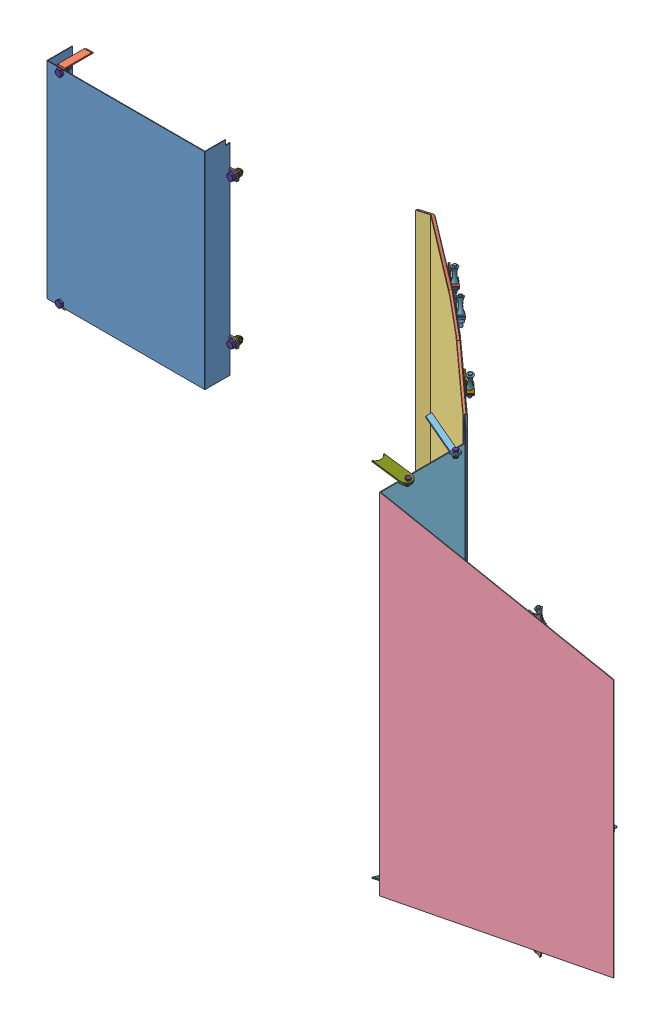
SolidWorks assembly PUTM-F-MS-SF-Firewall-Assembly, configuration Domyślna. Lengths in mm.
Overall size (1412.07 703.37 520.4).
48 component instances, 23 part files, 40 mates.
Components (placement in the parent):
- PUTM-F-MS-Firewall_Front_Aluminum_Skin-1: PUTM-F-MS-Firewall_Front_Aluminum_Skin [Domyślna] at origin size (454.25 703.37 375.65)
- PUTM-F-MS-Firewall_Front_Nomex_Core-1: PUTM-F-MS-Firewall_Front_Nomex_Core [Domyślna] at origin size (440.38 689.93 362.26)
- PUTM-F-MS-Firewall_Front_Kevlar_Skin-1: PUTM-F-MS-Firewall_Front_Kevlar_Skin [Domyślna] at origin size (443.17 703.37 363.44)
- PUTM-F-MS-SF-Firewall_Rear_Kevlar_Skin-1: PUTM-F-MS-SF-Firewall_Rear_Kevlar_Skin [Domyślna] at origin size (403.74 589.1 153.42)
- PUTM-F-MS-SF-Firewall_Rear_Aluminum_Skin-1: PUTM-F-MS-SF-Firewall_Rear_Aluminum_Skin [Domyślna] at origin size (403.45 588.99 153.27)
- PUTM-F-FR-MT-Firewall_Mountings_1-1: PUTM-F-FR-MT-Firewall_Mountings_1 [Domyślna] at origin size (23.76 25.91 22.22)
- PUTM-F-FR-MT-Firewall_Mounting_2-1: PUTM-F-FR-MT-Firewall_Mounting_2 [Domyślna] at origin size (28.34 29.8 21.98)
- PUTM-F-FR-MT-Firewall_Mountings_3-1: PUTM-F-FR-MT-Firewall_Mountings_3 [Domyślna] at origin size (22.95 27.42 25.34)
- LustroPUTM-F-FR-MT-Firewall_Mountings_3-2: LustroPUTM-F-FR-MT-Firewall_Mountings_3 [Domyślna] x (1 0 0) z (0 0 -1) size (22.95 27.42 25.34)
- LustroPUTM-F-FR-MT-Firewall_Mounting_2-2: LustroPUTM-F-FR-MT-Firewall_Mounting_2 [Domyślna] x (1 0 0) z (0 0 -1) size (28.34 29.8 21.98)
- LustroPUTM-F-FR-MT-Firewall_Mountings_1-2: LustroPUTM-F-FR-MT-Firewall_Mountings_1 [Domyślna] x (1 0 0) z (0 0 -1) size (23.76 25.91 22.22)
- PUTM-F-FR-MT-Firewall_Mountings_4-1: PUTM-F-FR-MT-Firewall_Mountings_4 [Domyślna] at origin size (26.62 34.9 12)
- LustroPUTM-F-FR-MT-Firewall_Mountings_4-2: LustroPUTM-F-FR-MT-Firewall_Mountings_4 [Domyślna] x (1 0 0) z (0 0 -1) size (26.62 34.9 12)
- PUTM-F-FR-MT-Firewall_Mounting_Cotter_Pin-1: PUTM-F-FR-MT-Firewall_Mounting_Cotter_Pin [Domyślna] at (801.96 -325.1095 318.2891) x (0.913742 -0.274504 0.299537) z (-0.223324 -0.955217 -0.194133) size (10 10 40.12)
- PUTM-F-FR-MT-Firewall_Mounting_Cotter_Pin-2: PUTM-F-FR-MT-Firewall_Mounting_Cotter_Pin [Domyślna] at (924.0825 -328.3705 419.9841) x (-0.719234 -0.211042 -0.66194) z (0.159337 -0.977459 0.138509) size (10 10 40.12)
- PUTM-F-FR-MT-Firewall_Mounting_Cotter_Pin-3: PUTM-F-FR-MT-Firewall_Mounting_Cotter_Pin [Domyślna] at (924.0825 328.3705 419.9841) x (0.719234 -0.211042 0.66194) z (0.159337 0.977459 0.138509) size (10 10 40.12)
- PUTM-F-FR-MT-Firewall_Mounting_Cotter_Pin-4: PUTM-F-FR-MT-Firewall_Mounting_Cotter_Pin [Domyślna] at (801.96 325.1095 318.2891) x (-0.913742 -0.274504 -0.299537) z (-0.223324 0.955217 -0.194133) size (10 10 40.12)
- PUTM-F-FR-MT-Firewall_Mounting_Cotter_Pin-5: PUTM-F-FR-MT-Firewall_Mounting_Cotter_Pin [Domyślna] at (726.1444 -299.3743 252.4949) x (0.879211 -0.045593 0.474246) z (-0.035265 -0.998908 -0.030655) size (10 10 40.12)
- PUTM-F-FR-MT-Firewall_Mounting_Cotter_Pin-6: PUTM-F-FR-MT-Firewall_Mounting_Cotter_Pin [Domyślna] at (726.1444 299.3743 252.4949) x (-0.879211 -0.045593 -0.474246) z (-0.035265 0.998908 -0.030655) size (10 10 40.12)
- PUTM-F-FR-MT-Firewall_Mounting_5-1: PUTM-F-FR-MT-Firewall_Mounting_5 [Domyślna] at origin size (54.5 12.56 22.24)
- LustroPUTM-F-FR-MT-Firewall_Mounting_5-2: LustroPUTM-F-FR-MT-Firewall_Mounting_5 [Domyślna] x (1 0 0) z (0 0 -1) size (54.5 12.56 22.24)
- PUTM-FT-FABORY_DIN933-1: PUTM-FT-FABORY_DIN933 [M4x10 [01210.040.010]] at (976.1401 295.562 577.4282) x (0.192233 0.981349 0) z (0 0 1) size (12.8 8.08 7)
- PUTM-FT-FABORY_DIN933-2: PUTM-FT-FABORY_DIN933 [M4x10 [01210.040.010]] at (976.1401 -295.562 577.4282) x (0.192233 -0.981349 0) z (0 0 1) size (12.8 8.08 7)
- PUTM-FT-FABORY_DIN985-1: PUTM-FT-FABORY_DIN985 [M4 [12348.040.001]] at (974.8329 288.8888 577.4282) x (0.943744 -0.184866 -0.274176) z (-0.192233 -0.981349 0) size (8.48 7.4 5.2)
- PUTM-FT-FABORY_DIN985-2: PUTM-FT-FABORY_DIN985 [M4 [12348.040.001]] at (974.8329 -288.8888 577.4282) x (0.899843 0.176267 -0.399013) z (-0.192233 0.981349 0) size (8.48 7.4 5.2)
- PUTM-F-MS-FW-LV_Firewall-1: PUTM-F-MS-FW-LV_Firewall [Domyślna] at origin size (277 344 42)
- PUTM-F-FR-MT-LV_Firewall_Mounting-2: PUTM-F-FR-MT-LV_Firewall_Mounting [Domyślna] at origin size (259.85 60.04 48.36)
- LustroPUTM-F-FR-MT-LV_Firewall_Mounting-3: LustroPUTM-F-FR-MT-LV_Firewall_Mounting [Domyślna] x (1 0 0) z (0 0 -1) size (259.85 60.04 48.36)
- PUTM-FT-FABORY_DIN933-3: PUTM-FT-FABORY_DIN933 [M6x16 [01210.060.016]] at (-28.852 -167.0403 157) x (0 0 1) z (0.417986 0.908453 0) size (20 11.55 10)
- PUTM-FT-FABORY_DIN933-5: PUTM-FT-FABORY_DIN933 [M6x16 [01210.060.016]] at (219 121 118.6) x (0 0 1) z (-0.91356 -0.406705 0) size (20 11.55 10)
- PUTM-FT-FABORY_DIN933-6: PUTM-FT-FABORY_DIN933 [M6x16 [01210.060.016]] at (-28.852 167.0403 157) x (0 0 1) z (-0.861615 -0.507562 0) size (20 11.55 10)
- PUTM-FT-FABORY_DIN933-10: PUTM-FT-FABORY_DIN933 [M6x16 [01210.060.016]] at (219 -121 118.6) x (0 0 1) z (-0.889465 -0.457003 0) size (20 11.55 10)
- PUTM-FT-FABORY_ISO7089-4: PUTM-FT-FABORY_ISO7089 [M6 [38093.060.001]] at (219 121 113) size (12 12 1.6)
- PUTM-FT-FABORY_ISO7089-5: PUTM-FT-FABORY_ISO7089 [M6 [38093.060.001]] at (219 -121 113) size (12 12 1.6)
- PUTM-FT-FABORY_ISO7089-15: PUTM-FT-FABORY_ISO7089 [M6 [38093.060.001]] at (219 121 107.4) size (12 12 1.6)
- PUTM-FT-FABORY_ISO7089-16: PUTM-FT-FABORY_ISO7089 [M6 [38093.060.001]] at (219 -121 107.4) size (12 12 1.6)
- PUTM-FT-FABORY_DIN985-5: PUTM-FT-FABORY_DIN985 [M6 [12348.060.001]] at (219 -121 107.4) x (-0.99791 -0.064621 0) z (0 0 -1) size (11.9 10.35 6.18)
- PUTM-FT-FABORY_DIN985-9: PUTM-FT-FABORY_DIN985 [M6 [12348.060.001]] at (219 121 107.4) x (-0.942958 0.332911 0) z (0 0 -1) size (11.9 10.35 6.18)
- PUTM-FT-FABORY_DIN985-10: PUTM-FT-FABORY_DIN985 [M6 [12348.060.001]] at (-28.852 167.0403 150) x (0.341689 -0.939813 0) z (0 0 -1) size (11.9 10.35 6.18)
- PUTM-FT-FABORY_DIN985-11: PUTM-FT-FABORY_DIN985 [M6 [12348.060.001]] at (-28.852 -167.0403 150) x (-0.356012 -0.934481 0) z (0 0 -1) size (11.9 10.35 6.18)
- PUTM-F-FR-MT-Firewall_Mounting_6-1: PUTM-F-FR-MT-Firewall_Mounting_6 [Domyślna] at origin size (50.77 32.6 10)
- PUTM-F-FR-MT-Firewall_Mounting_6-2: PUTM-F-FR-MT-Firewall_Mounting_6 [Domyślna] at (0 0 995.9987) x (1 0 0) z (0 0 -1) size (50.77 32.6 10)
- PUTM-FT-FABORY_DIN933-11: PUTM-FT-FABORY_DIN933 [M4x10 [01210.040.010]] at (975.5827 296.5593 497.9993) x (0 1 0) z (0 0 1) size (12.8 8.08 7)
- PUTM-FT-FABORY_DIN933-12: PUTM-FT-FABORY_DIN933 [M4x10 [01210.040.010]] at (975.5827 -296.5593 497.9993) x (0 -1 0) z (0 0 1) size (12.8 8.08 7)
- PUTM-FT-FABORY_DIN985-12: PUTM-FT-FABORY_DIN985 [M4 [12348.040.001]] at (975.5827 289.7593 497.9993) x (0.916837 0 0.399261) z (0 -1 0) size (8.48 7.4 5.2)
- PUTM-FT-FABORY_DIN985-13: PUTM-FT-FABORY_DIN985 [M4 [12348.040.001]] at (975.5827 -289.7593 497.9993) x (1 0 0) z (0 1 0) size (8.48 7.4 5.2)
- PUTM-F-FR-MT-Firewall_Mounting_Cotter_Pin-7: PUTM-F-FR-MT-Firewall_Mounting_Cotter_Pin [Domyślna] at (1230.8841 -235.5415 608.9586) x (-0.569792 0.172434 -0.803495) z (-0.289653 -0.957132 0) size (10 10 40.12)
- PUTM-F-FR-MT-Firewall_Mounting_Cotter_Pin-8: PUTM-F-FR-MT-Firewall_Mounting_Cotter_Pin [Domyślna] at (1230.8841 235.5415 608.9586) x (0.569792 0.172434 0.803495) z (-0.289653 0.957132 0) size (10 10 40.12)
Mates (geometry in assembly coordinates):
- Koncentryczne22: concentric anti-aligned: cylinder of LustroPUTM-F-FR-MT-Firewall_Mountings_3-2 through (919.9227 310.1146 418.6836) axis (0.159337 0.977459 0.138509) radius 2.5; cylinder of PUTM-F-FR-MT-Firewall_Mounting_Cotter_Pin-3 through (918.9666 304.2499 417.8525) axis (-0.159337 -0.977459 -0.138509) radius 2.5
- Wspólnie1: coincident anti-aligned: plane of LustroPUTM-F-FR-MT-Firewall_Mountings_3-2 through (932.1733 317.778 422.7079) normal (0.159337 0.977459 0.138509); plane of PUTM-F-FR-MT-Firewall_Mounting_Cotter_Pin-3 through (923.2066 319.8746 418.2271) normal (-0.159337 -0.977459 -0.138509)
- Koncentryczne23: concentric aligned: cylinder of PUTM-F-MS-Firewall_Front_Aluminum_Skin-1 through (804.0468 -318.5285 317.9542) axis (0.223324 0.955217 0.194133) radius 2.5; cylinder of PUTM-F-FR-MT-Firewall_Mounting_Cotter_Pin-1 through (808.0666 -301.3346 321.4486) axis (0.223324 0.955217 0.194133) radius 2.5
- Wspólnie2: coincident anti-aligned: plane of PUTM-F-FR-MT-Firewall_Mounting_2-1 through (814.9828 -319.5771 320.8357) normal (-0.223324 -0.955217 -0.194133); plane of PUTM-F-FR-MT-Firewall_Mounting_Cotter_Pin-1 through (803.6449 -316.8943 320.6778) normal (0.223324 0.955217 0.194133)
- Koncentryczne24: concentric anti-aligned: cylinder of PUTM-F-FR-MT-Firewall_Mountings_1-1 through (727.634 -280.6895 251.5296) axis (-0.035265 -0.998908 -0.030655) radius 2.5; cylinder of PUTM-F-FR-MT-Firewall_Mounting_Cotter_Pin-5 through (727.8456 -274.6961 251.7135) axis (0.035265 0.998908 0.030655) radius 2.5
- Wspólnie3: coincident anti-aligned: plane of PUTM-F-FR-MT-Firewall_Mountings_1-1 through (738.1005 -291.1458 254.0029) normal (-0.035265 -0.998908 -0.030655); plane of PUTM-F-FR-MT-Firewall_Mounting_Cotter_Pin-5 through (726.0935 -290.7042 253.4227) normal (0.035265 0.998908 0.030655)
- Koncentryczne27: concentric aligned: cylinder of PUTM-F-MS-FW-LV_Firewall-1 through (219 121 113) axis (0 0 -1) radius 3; cylinder of PUTM-FT-FABORY_DIN933-5 through (219 121 98.6) axis (0 0 -1) radius 3
- Koncentryczne32: concentric aligned: cylinder of PUTM-F-MS-FW-LV_Firewall-1 through (219 -121 113) axis (0 0 -1) radius 3; cylinder of PUTM-FT-FABORY_DIN933-10 through (219 -121 98.6) axis (0 0 -1) radius 3
- Koncentryczne38: concentric aligned: cylinder of PUTM-FT-FABORY_DIN933-5 through (219 121 98.6) axis (0 0 -1) radius 3; cylinder of PUTM-FT-FABORY_ISO7089-4 through (219 121 114.6) axis (0 0 -1) radius 3.2
- Koncentryczne39: concentric aligned: cylinder of PUTM-FT-FABORY_DIN933-10 through (219 -121 98.6) axis (0 0 -1) radius 3; cylinder of PUTM-FT-FABORY_ISO7089-5 through (219 -121 114.6) axis (0 0 -1) radius 3.2
- Koncentryczne45: concentric aligned: cylinder of PUTM-FT-FABORY_DIN933-5 through (219 121 98.6) axis (0 0 -1) radius 3; cylinder of PUTM-FT-FABORY_ISO7089-15 through (219 121 109) axis (0 0 -1) radius 3.2
- Koncentryczne46: concentric aligned: cylinder of PUTM-FT-FABORY_DIN933-10 through (219 -121 98.6) axis (0 0 -1) radius 3; cylinder of PUTM-FT-FABORY_ISO7089-16 through (219 -121 109) axis (0 0 -1) radius 3.2
- Wspólnie18: coincident anti-aligned: plane of PUTM-FT-FABORY_DIN933-5 through (216.9665 125.5678 114.6) normal (0 0 -1); plane of PUTM-FT-FABORY_ISO7089-4 through (219 121 114.6) normal (0 0 1)
- Wspólnie19: coincident anti-aligned: plane of PUTM-F-MS-FW-LV_Firewall-1 through (0 0 113) normal (0 0 1); plane of PUTM-FT-FABORY_ISO7089-4 through (219 121 113) normal (0 0 -1)
- Wspólnie20: coincident anti-aligned: plane of PUTM-F-FR-MT-LV_Firewall_Mounting-2 through (225 127 109) normal (0 0 -1); plane of PUTM-FT-FABORY_ISO7089-15 through (219 121 109) normal (0 0 1)
- Wspólnie21: coincident anti-aligned: plane of PUTM-FT-FABORY_DIN933-10 through (216.715 -116.5527 114.6) normal (0 0 -1); plane of PUTM-FT-FABORY_ISO7089-5 through (219 -121 114.6) normal (0 0 1)
- Wspólnie22: coincident anti-aligned: plane of PUTM-F-MS-FW-LV_Firewall-1 through (0 0 113) normal (0 0 1); plane of PUTM-FT-FABORY_ISO7089-5 through (219 -121 113) normal (0 0 -1)
- Wspólnie23: coincident anti-aligned: plane of LustroPUTM-F-FR-MT-LV_Firewall_Mounting-3 through (225 -127 109) normal (0 0 -1); plane of PUTM-FT-FABORY_ISO7089-16 through (219 -121 109) normal (0 0 1)
- Koncentryczne48: concentric anti-aligned: cylinder of PUTM-FT-FABORY_DIN933-10 through (219 -121 98.6) axis (0 0 -1) radius 3; cylinder of PUTM-FT-FABORY_DIN985-5 through (219 -121 103.4) axis (0 0 1) radius 3
- Wspólnie35: coincident anti-aligned: plane of PUTM-FT-FABORY_ISO7089-16 through (219 -121 107.4) normal (0 0 -1); plane of PUTM-FT-FABORY_DIN985-5 through (219 -121 107.4) normal (0 0 1)
- Koncentryczne53: concentric anti-aligned: cylinder of PUTM-FT-FABORY_DIN933-5 through (219 121 98.6) axis (0 0 -1) radius 3; cylinder of PUTM-FT-FABORY_DIN985-9 through (219 121 103.4) axis (0 0 1) radius 3
- Wspólnie39: coincident anti-aligned: plane of PUTM-FT-FABORY_ISO7089-15 through (219 121 107.4) normal (0 0 -1); plane of PUTM-FT-FABORY_DIN985-9 through (219 121 107.4) normal (0 0 1)
- Wspólnie40: coincident: plane of PUTM-F-FR-MT-LV_Firewall_Mounting-2 through (-22.852 161.0403 150) normal (0 0 -1); plane of PUTM-FT-FABORY_DIN985-10 through (-28.852 167.0403 150) normal (0 0 1)
- Koncentryczne57: concentric anti-aligned: cylinder of PUTM-F-FR-MT-Firewall_Mounting_6-2 through (975.5827 283.7593 497.9993) axis (0 1 0) radius 2; cylinder of PUTM-FT-FABORY_DIN933-11 through (975.5827 283.7593 497.9993) axis (0 -1 0) radius 2
- Wspólnie44: coincident anti-aligned: plane of PUTM-F-FR-MT-Firewall_Mounting_6-2 through (980.5827 293.7593 502.9993) normal (0 1 0); plane of PUTM-FT-FABORY_DIN933-11 through (972.0827 293.7593 497.9993) normal (0 -1 0)
- Koncentryczne58: concentric anti-aligned: cylinder of PUTM-F-FR-MT-Firewall_Mounting_6-1 through (975.5827 -283.7593 497.9993) axis (0 -1 0) radius 2; cylinder of PUTM-FT-FABORY_DIN933-12 through (975.5827 -283.7593 497.9993) axis (0 1 0) radius 2
- Wspólnie45: coincident anti-aligned: plane of PUTM-F-FR-MT-Firewall_Mounting_6-1 through (980.5827 -293.7593 492.9993) normal (0 -1 0); plane of PUTM-FT-FABORY_DIN933-12 through (979.0827 -293.7593 497.9993) normal (0 1 0)
- Koncentryczne59: concentric anti-aligned: cylinder of PUTM-FT-FABORY_DIN933-11 through (975.5827 283.7593 497.9993) axis (0 -1 0) radius 2; cylinder of PUTM-FT-FABORY_DIN985-12 through (975.5827 286.8593 497.9993) axis (0 1 0) radius 2
- Wspólnie46: coincident anti-aligned: plane of PUTM-F-MS-SF-Firewall_Rear_Aluminum_Skin-1 through (980.5827 289.7593 502.9993) normal (0 -1 0); plane of PUTM-FT-FABORY_DIN985-12 through (975.5827 289.7593 497.9993) normal (0 1 0)
- Koncentryczne60: concentric anti-aligned: cylinder of PUTM-FT-FABORY_DIN933-12 through (975.5827 -283.7593 497.9993) axis (0 1 0) radius 2; cylinder of PUTM-FT-FABORY_DIN985-13 through (975.5827 -286.8593 497.9993) axis (0 -1 0) radius 2
- Wspólnie47: coincident anti-aligned: plane of PUTM-F-MS-SF-Firewall_Rear_Aluminum_Skin-1 through (980.5827 -289.7593 502.9993) normal (0 1 0); plane of PUTM-FT-FABORY_DIN985-13 through (975.5827 -289.7593 497.9993) normal (0 -1 0)
- Koncentryczne61: concentric aligned: cylinder of LustroPUTM-F-FR-MT-LV_Firewall_Mounting-3 through (-28.852 -167.0403 162) axis (0 0 -1) radius 3; cylinder of PUTM-FT-FABORY_DIN933-3 through (-28.852 -167.0403 137) axis (0 0 -1) radius 3
- Wspólnie55: coincident anti-aligned: plane of PUTM-F-MS-FW-LV_Firewall-1 through (211 -172 153) normal (0 0 1); plane of PUTM-FT-FABORY_DIN933-3 through (-24.3097 -169.1303 153) normal (0 0 -1)
- Koncentryczne65: concentric anti-aligned: cylinder of PUTM-FT-FABORY_DIN933-3 through (-28.852 -167.0403 137) axis (0 0 -1) radius 3; cylinder of PUTM-FT-FABORY_DIN985-11 through (-28.852 -167.0403 146) axis (0 0 1) radius 3
- Wspólnie56: coincident anti-aligned: plane of LustroPUTM-F-FR-MT-LV_Firewall_Mounting-3 through (-22.852 -161.0403 150) normal (0 0 -1); plane of PUTM-FT-FABORY_DIN985-11 through (-28.852 -167.0403 150) normal (0 0 1)
- Koncentryczne66: concentric aligned: cylinder of PUTM-F-FR-MT-LV_Firewall_Mounting-2 through (-28.852 167.0403 162) axis (0 0 -1) radius 3; cylinder of PUTM-FT-FABORY_DIN933-6 through (-28.852 167.0403 137) axis (0 0 -1) radius 3
- Wspólnie57: coincident anti-aligned: plane of PUTM-F-MS-FW-LV_Firewall-1 through (211 -172 153) normal (0 0 1); plane of PUTM-FT-FABORY_DIN933-6 through (-31.3898 171.3484 153) normal (0 0 -1)
- Koncentryczne69: concentric anti-aligned: cylinder of PUTM-FT-FABORY_DIN933-6 through (-28.852 167.0403 137) axis (0 0 -1) radius 3; cylinder of PUTM-FT-FABORY_DIN985-10 through (-28.852 167.0403 146) axis (0 0 1) radius 3
- Concentric1: concentric aligned: cylinder of PUTM-F-FR-MT-Firewall_Mountings_4-1 through (1229.1594 -236.3911 609.9993) axis (0.289653 0.957132 0) radius 2.5; cylinder of PUTM-F-FR-MT-Firewall_Mounting_Cotter_Pin-7 through (1236.6904 -211.5056 609.9993) axis (0.289653 0.957132 0) radius 2.5
- Tangent1: tangent anti-aligned: cylinder of PUTM-F-FR-MT-Firewall_Mountings_4-1 through (1233.5042 -222.0341 605.9993) axis (0 0 1) radius 5; plane of PUTM-F-FR-MT-Firewall_Mounting_Cotter_Pin-7 through (1233.9786 -227.4016 608.5111) normal (0.289653 0.957132 0)
